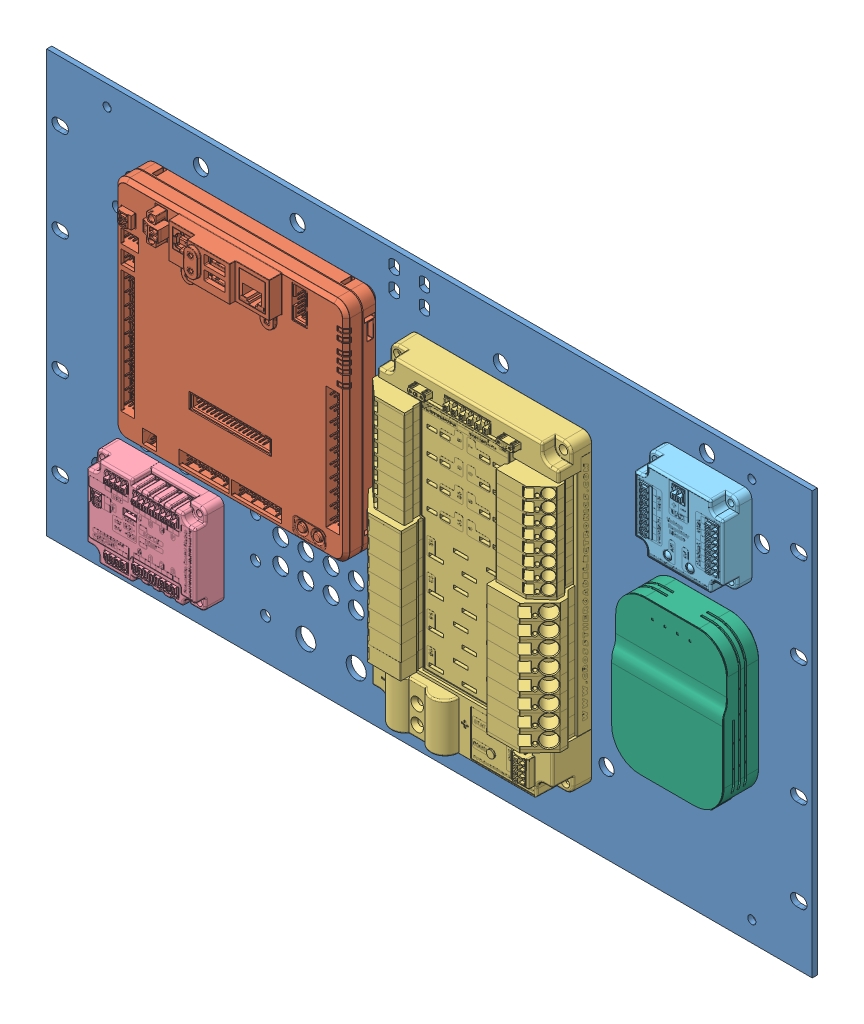
SolidWorks assembly Core Panel Assembly, configuration Default. Lengths in mm.
Overall size (482.6 265.94 39.93).
6 component instances, 6 part files, 13 mates.
Components (placement in the parent):
- Panel-1: Panel [Default] at (181.0216 243.6318 373.9663) size (482.6 265.94 3.17)
- roboRIO-1: roboRIO [Default] at (76.2974 279.6109 386.7933) size (146.27 143.19 36.83)
- PDP-1: PDP [Default] at (225.971 246.4811 383.8215) x (0 1 0) z (1 0 0) size (192.68 36.15 120.93)
- PCM-1: PCM [Default] at (16.8837 158.1608 381.6117) x (1 0 0) z (0 -1 0) size (69.09 19.67 56.9)
- VRM-1: VRM [Default] at (355.496 329.854 384.2727) x (-1 0 0) z (0 1 0) size (56.39 19.92 51.56)
- OM5P-AN-1: OM5P-AN [Default] at (321.2973 192.9278 377.1413) x (1 0 0) z (0 -1 0) size (69.89 25.47 95.8)
Mates (geometry in assembly coordinates):
- Coincident1: coincident aligned: plane of Panel-1 through (181.0216 243.6318 377.1413) normal (0 0 1); plane of roboRIO-1 through (2.7854 207.6442 377.1413) normal (0 0 1)
- Coincident2: coincident anti-aligned: plane of Panel-1 through (181.0216 243.6318 377.1413) normal (0 0 1); plane of PDP-1 through (173.774 333.2983 377.1413) normal (0 0 -1)
- Parallel2: parallel: plane of Panel-1 through (422.3216 376.6008 377.1413) normal (1 0 0); line of PDP-1 through (283.3705 328.7218 377.3997) axis (0 -1 0)
- Distance1: distance = 25.4 mm anti-aligned: plane of roboRIO-1 through (144.3715 351.2008 379.3734) normal (0 -1 0); plane of Panel-1 through (-60.2784 376.6008 377.1413) normal (0 1 0)
- Distance2: distance = 63.5 mm anti-aligned: plane of roboRIO-1 through (3.2216 346.1396 379.3734) normal (1 0 0); plane of Panel-1 through (-60.2784 376.6008 377.1413) normal (-1 0 0)
- Distance3: distance = 38.1 mm: line of PDP-1 through (278.1643 338.5008 377.3997) axis (-1 0 0); plane of Panel-1 through (-60.2784 376.6008 377.1413) normal (0 1 0)
- Coincident8: coincident anti-aligned: plane of Panel-1 through (181.0216 243.6318 377.1413) normal (0 0 1); plane of PCM-1 through (-14.1043 183.0528 377.1413) normal (0 0 -1)
- Coincident11: coincident anti-aligned: plane of Panel-1 through (181.0216 243.6318 377.1413) normal (0 0 1); plane of VRM-1 through (332.1516 310.3068 377.1413) normal (0 0 -1)
- Coincident12: coincident anti-aligned: plane of Panel-1 through (181.0216 243.6318 377.1413) normal (0 0 1); plane of OM5P-AN-1 through (379.6534 276.684 377.1413) normal (0 0 -1)
- Parallel5: parallel: plane of Panel-1 through (422.3216 376.6008 377.1413) normal (1 0 0); line of VRM-1 through (384.2216 310.3068 377.1413) axis (0 1 0)
- Distance4: distance = 19.05 mm: line of PCM-1 through (-14.1043 129.7128 377.1413) axis (1 0 0); plane of Panel-1 through (-60.2784 110.6628 377.1413) normal (0 -1 0)
- Distance5: distance = 12.7 mm: line of VRM-1 through (384.2216 310.3068 377.1413) axis (0 1 0); line of assembly
- Distance6: distance = 19.05 mm: line of VRM-1 through (379.9036 357.5508 377.1413) axis (-1 0 0); plane of Panel-1 through (-60.2784 376.6008 377.1413) normal (0 1 0)
